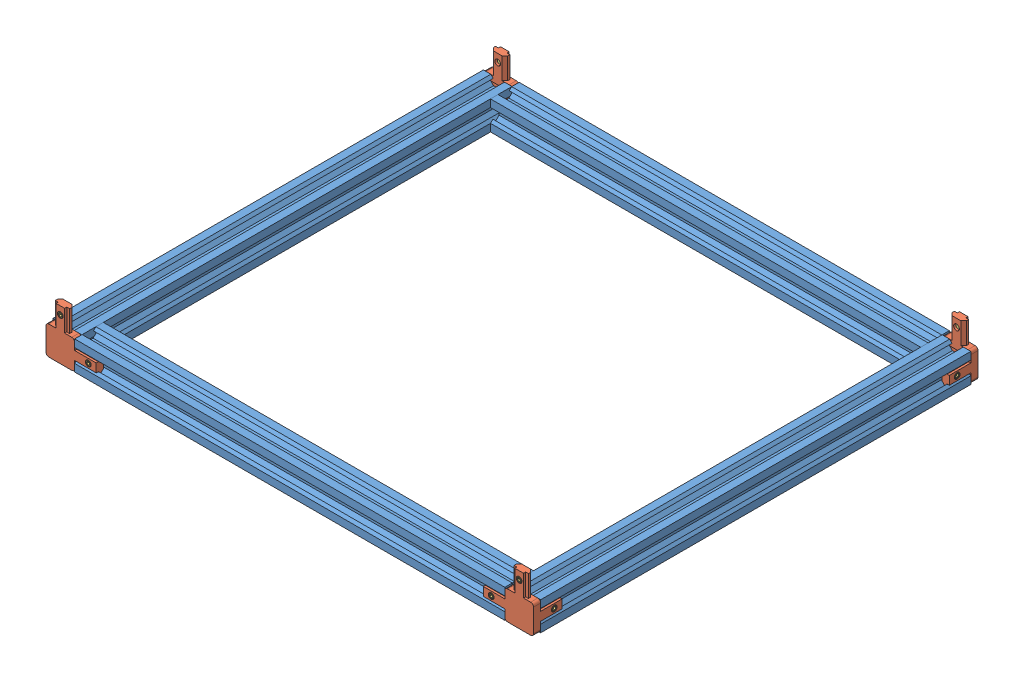
SolidWorks assembly Base, configuration Default. Lengths in mm.
Overall size (340.57 35.29 310.57).
24 component instances, 3 part files, 31 mates.
Components (placement in the parent):
- V-slot-aluminum-1: V-slot-aluminum [side] at (-150 0 145) x (0 0 1) z (1 0 0) size (20 20 300)
- V-slot-aluminum-2: V-slot-aluminum [side] at (150 0 -145) x (0 0 -1) z (-1 0 0) size (20 20 300)
- V-slot-aluminum-3: V-slot-aluminum [front] at (160 0 -150) size (20 20 300)
- V-slot-aluminum-4: V-slot-aluminum [front] at (-160 0 -150) x (-1 0 0) z (0 0 1) size (20 20 300)
- 2020 3-way corner bracket-1: 2020 3-way corner bracket [Default] at (-150 10 155) x (-1 0 0) z (0 0 1) size (35 35 20)
- 2020 3-way corner bracket-2: 2020 3-way corner bracket [Default] at (150 10 -155) x (1 0 0) z (0 0 -1) size (35 35 20)
- 2020 3-way corner bracket-3: 2020 3-way corner bracket [Default] at (-150 10 -155) x (0 -1 0) z (0 0 -1) size (35 35 20)
- 2020 3-way corner bracket-4: 2020 3-way corner bracket [Default] at (150 10 155) x (0 -1 0) z (0 0 1) size (35 35 20)
- 92605A657_Stainless Steel Flat-Tip Set Screw-1: 92605A657_Stainless Steel Flat-Tip Set Screw [92605A657] at (-160 -8 140.5) x (-0.546944 0 0.837169) z (0 -1 0) size (4.62 4.11 4.33)
- 92605A657_Stainless Steel Flat-Tip Set Screw-2: 92605A657_Stainless Steel Flat-Tip Set Screw [92605A657] at (-140.5 0 153) size (4.62 4.11 4.33)
- 92605A657_Stainless Steel Flat-Tip Set Screw-3: 92605A657_Stainless Steel Flat-Tip Set Screw [92605A657] at (-168 0 140.5) x (0 0.383049 -0.923728) z (-1 0 0) size (4.62 4.11 4.33)
- 92605A657_Stainless Steel Flat-Tip Set Screw-4: 92605A657_Stainless Steel Flat-Tip Set Screw [92605A657] at (-160 19.5 153) x (-0.381849 -0.924225 0) z (0 0 1) size (4.62 4.11 4.33)
- 92605A657_Stainless Steel Flat-Tip Set Screw-5: 92605A657_Stainless Steel Flat-Tip Set Screw [92605A657] at (140.5 0 -153) x (-1 0 0) z (0 0 -1) size (4.62 4.11 4.33)
- 92605A657_Stainless Steel Flat-Tip Set Screw-6: 92605A657_Stainless Steel Flat-Tip Set Screw [92605A657] at (160 19.5 -153) x (0.381849 -0.924225 0) z (0 0 -1) size (4.62 4.11 4.33)
- 92605A657_Stainless Steel Flat-Tip Set Screw-7: 92605A657_Stainless Steel Flat-Tip Set Screw [92605A657] at (160 -8 -140.5) x (0.546944 0 -0.837169) z (0 -1 0) size (4.62 4.11 4.33)
- 92605A657_Stainless Steel Flat-Tip Set Screw-8: 92605A657_Stainless Steel Flat-Tip Set Screw [92605A657] at (168 0 -140.5) x (0 0.383049 0.923728) z (1 0 0) size (4.62 4.11 4.33)
- 92605A657_Stainless Steel Flat-Tip Set Screw-17: 92605A657_Stainless Steel Flat-Tip Set Screw [92605A657] at (160.0846 -8 140.4448) x (0.546944 0 0.837169) z (0 -1 0) size (4.62 4.11 4.33)
- 92605A657_Stainless Steel Flat-Tip Set Screw-18: 92605A657_Stainless Steel Flat-Tip Set Screw [92605A657] at (159.9066 19.4614 153) x (0.381849 -0.924225 0) z (0 0 1) size (4.62 4.11 4.33)
- 92605A657_Stainless Steel Flat-Tip Set Screw-19: 92605A657_Stainless Steel Flat-Tip Set Screw [92605A657] at (168 -0.0933 140.4613) x (0 0.383049 -0.923728) z (1 0 0) size (4.62 4.11 4.33)
- 92605A657_Stainless Steel Flat-Tip Set Screw-20: 92605A657_Stainless Steel Flat-Tip Set Screw [92605A657] at (140.5 0.101 153) x (-1 0 0) z (0 0 1) size (4.62 4.11 4.33)
- 92605A657_Stainless Steel Flat-Tip Set Screw-21: 92605A657_Stainless Steel Flat-Tip Set Screw [92605A657] at (-140.5 0.101 -153) x (1 0 0) z (0 0 -1) size (4.62 4.11 4.33)
- 92605A657_Stainless Steel Flat-Tip Set Screw-22: 92605A657_Stainless Steel Flat-Tip Set Screw [92605A657] at (-159.9066 19.4614 -153) x (-0.381849 -0.924225 0) z (0 0 -1) size (4.62 4.11 4.33)
- 92605A657_Stainless Steel Flat-Tip Set Screw-23: 92605A657_Stainless Steel Flat-Tip Set Screw [92605A657] at (-160.0846 -8 -140.4448) x (-0.546944 0 -0.837169) z (0 -1 0) size (4.62 4.11 4.33)
- 92605A657_Stainless Steel Flat-Tip Set Screw-24: 92605A657_Stainless Steel Flat-Tip Set Screw [92605A657] at (-168 -0.0933 -140.4613) x (0 0.383049 0.923728) z (-1 0 0) size (4.62 4.11 4.33)
Mates (geometry in assembly coordinates):
- Coincident4: coincident anti-aligned: plane of V-slot-aluminum-1 through (150 0 145) normal (1 0 0); plane of V-slot-aluminum-3 through (150 -4.775 150) normal (-1 0 0)
- Coincident5: coincident aligned: plane of V-slot-aluminum-1 through (150 4.775 155) normal (0 0 1); plane of 2020 3-way corner bracket-4 through (152.5 7.5 155) normal (0 0 1)
- Coincident6: coincident aligned: plane of V-slot-aluminum-1 through (150 -10 135) normal (0 -1 0); plane of 2020 3-way corner bracket-4 through (170 -10 155) normal (0 -1 0)
- Coincident7: coincident aligned: plane of V-slot-aluminum-1 through (150 4.775 155) normal (0 0 1); plane of 2020 3-way corner bracket-1 through (-152.5 7.5 155) normal (0 0 1)
- Coincident8: coincident anti-aligned: plane of V-slot-aluminum-1 through (-150 0 145) normal (-1 0 0); plane of 2020 3-way corner bracket-1 through (-150 -5 155) normal (1 0 0)
- Coincident9: coincident aligned: plane of V-slot-aluminum-1 through (150 -10 149.775) normal (0 -1 0); plane of 2020 3-way corner bracket-1 through (-150 -10 155) normal (0 -1 0)
- Coincident16: coincident anti-aligned: plane of V-slot-aluminum-2 through (150 0 -145) normal (1 0 0); plane of 2020 3-way corner bracket-2 through (150 10 -155) normal (-1 0 0)
- Coincident17: coincident aligned: plane of V-slot-aluminum-2 through (-150 -10 -135) normal (0 -1 0); plane of 2020 3-way corner bracket-2 through (150 -10 -155) normal (0 -1 0)
- Coincident18: coincident aligned: plane of V-slot-aluminum-2 through (-150 -10 -155) normal (0 0 -1); plane of 2020 3-way corner bracket-2 through (152.5 7.5 -155) normal (0 0 -1)
- Coincident1: coincident anti-aligned: plane of V-slot-aluminum-3 through (160 0 150) normal (0 0 1); plane of 2020 3-way corner bracket-4 through (152.5 7.5 150) normal (0 0 -1)
- Coincident2: coincident aligned: plane of V-slot-aluminum-3 through (170 10 150) normal (1 0 0); plane of 2020 3-way corner bracket-4 through (170 10 155) normal (1 0 0)
- Coincident3: coincident aligned: plane of V-slot-aluminum-3 through (164.775 -10 150) normal (0 -1 0); plane of 2020 3-way corner bracket-4 through (170 -10 155) normal (0 -1 0)
- Coincident13: coincident anti-aligned: plane of V-slot-aluminum-3 through (160 0 -150) normal (0 0 -1); plane of 2020 3-way corner bracket-2 through (152.5 7.5 -150) normal (0 0 1)
- Coincident14: coincident aligned: plane of V-slot-aluminum-3 through (164.775 -10 150) normal (0 -1 0); plane of 2020 3-way corner bracket-2 through (150 -10 -155) normal (0 -1 0)
- Coincident15: coincident aligned: plane of V-slot-aluminum-3 through (170 -4.775 150) normal (1 0 0); plane of 2020 3-way corner bracket-2 through (170 -10 -155) normal (1 0 0)
- Coincident10: coincident anti-aligned: plane of V-slot-aluminum-4 through (-160 0 150) normal (0 0 1); plane of 2020 3-way corner bracket-1 through (-152.5 7.5 150) normal (0 0 -1)
- Coincident11: coincident aligned: plane of V-slot-aluminum-4 through (-164.775 -10 150) normal (0 -1 0); plane of 2020 3-way corner bracket-1 through (-150 -10 155) normal (0 -1 0)
- Coincident12: coincident aligned: plane of V-slot-aluminum-4 through (-170 -10 150) normal (-1 0 0); plane of 2020 3-way corner bracket-1 through (-170 -10 155) normal (-1 0 0)
- Coincident19: coincident anti-aligned: plane of V-slot-aluminum-4 through (-160 0 -150) normal (0 0 -1); plane of 2020 3-way corner bracket-3 through (-152.5 7.5 -150) normal (0 0 1)
- Coincident20: coincident aligned: plane of V-slot-aluminum-4 through (-170 -10 150) normal (-1 0 0); plane of 2020 3-way corner bracket-3 through (-170 10 -155) normal (-1 0 0)
- Coincident21: coincident aligned: plane of V-slot-aluminum-4 through (-164.775 -10 150) normal (0 -1 0); plane of 2020 3-way corner bracket-3 through (-170 -10 -155) normal (0 -1 0)
- Concentric22: concentric aligned: cylinder of 2020 3-way corner bracket-1 through (-160 -10 140.5) axis (0 1 0) radius 2; circle of 92605A657_Stainless Steel Flat-Tip Set Screw-1
- Coincident62: coincident aligned: plane of 2020 3-way corner bracket-1 through (-150 -10 155) normal (0 -1 0); plane of 92605A657_Stainless Steel Flat-Tip Set Screw-1 through (-160 -10 140.5) normal (0 -1 0)
- Concentric21: concentric aligned: cylinder of 2020 3-way corner bracket-1 through (-140.5 0 155) axis (0 0 -1) radius 2; cone of 92605A657_Stainless Steel Flat-Tip Set Screw-2 through (-140.5 0 151) axis (0 0 -1)
- Coincident61: coincident aligned: plane of 2020 3-way corner bracket-1 through (-152.5 7.5 155) normal (0 0 1); plane of 92605A657_Stainless Steel Flat-Tip Set Screw-2 through (-140.5 0 155) normal (0 0 1)
- Concentric19: concentric aligned: cylinder of 2020 3-way corner bracket-1 through (-170 0 140.5) axis (1 0 0) radius 2; circle of 92605A657_Stainless Steel Flat-Tip Set Screw-3
- Coincident58: coincident aligned: plane of 2020 3-way corner bracket-1 through (-170 -10 155) normal (-1 0 0); plane of 92605A657_Stainless Steel Flat-Tip Set Screw-3 through (-170 0 140.5) normal (-1 0 0)
- Concentric20: concentric aligned: cylinder of 2020 3-way corner bracket-1 through (-160 19.5 155) axis (0 0 -1) radius 2; circle of 92605A657_Stainless Steel Flat-Tip Set Screw-4
- Coincident60: coincident aligned: plane of 2020 3-way corner bracket-1 through (-152.5 7.5 155) normal (0 0 1); plane of 92605A657_Stainless Steel Flat-Tip Set Screw-4 through (-160 19.5 155) normal (0 0 1)
- Distance1: distance = 145 mm: plane of assembly through (0 0 0) normal (0 0 1); plane of assembly; plane of V-slot-aluminum-1 through (-150 0 145) normal (0 0 1)
- Distance3: distance = 160 mm aligned: plane of V-slot-aluminum-3 through (160 0 -150) normal (1 0 0)
